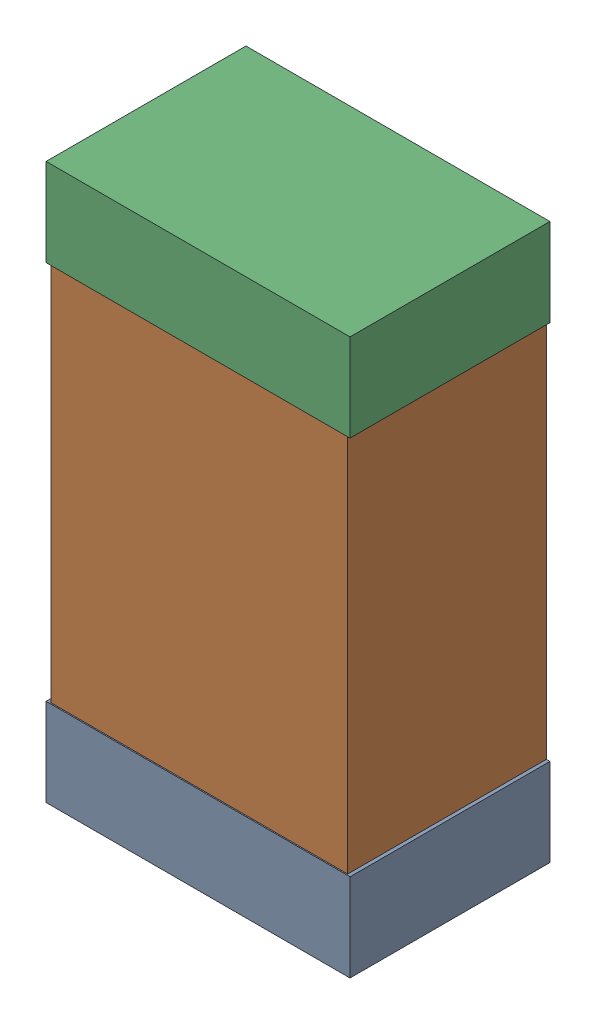
SolidWorks assembly C3Kanaloa_v2.0.0_Motor, configuration Default. Lengths in mm.
Overall size (1.3 2.38 0.85).
6 component instances, 2 part files, 0 mates.
Components (placement in the parent):
- 330415056-1: 330415056 [Default] at (85.344 119.65 0) size (1.3 0.38 0.85)
  - Extruded_2-1: Extruded_2 [Default] at origin size (1.3 0.38 0.85)
- 334787376-1: 334787376 [Default] at (85.344 120.65 0) size (1.27 2.2 0.85)
  - Extruded_16-1: Extruded_16 [Default] at origin size (1.27 2.2 0.85)
- 330415056-2: 330415056 [Default] at (85.344 121.65 0) size (1.3 0.38 0.85)
  - Extruded_2-1: Extruded_2 [Default] at origin size (1.3 0.38 0.85)
